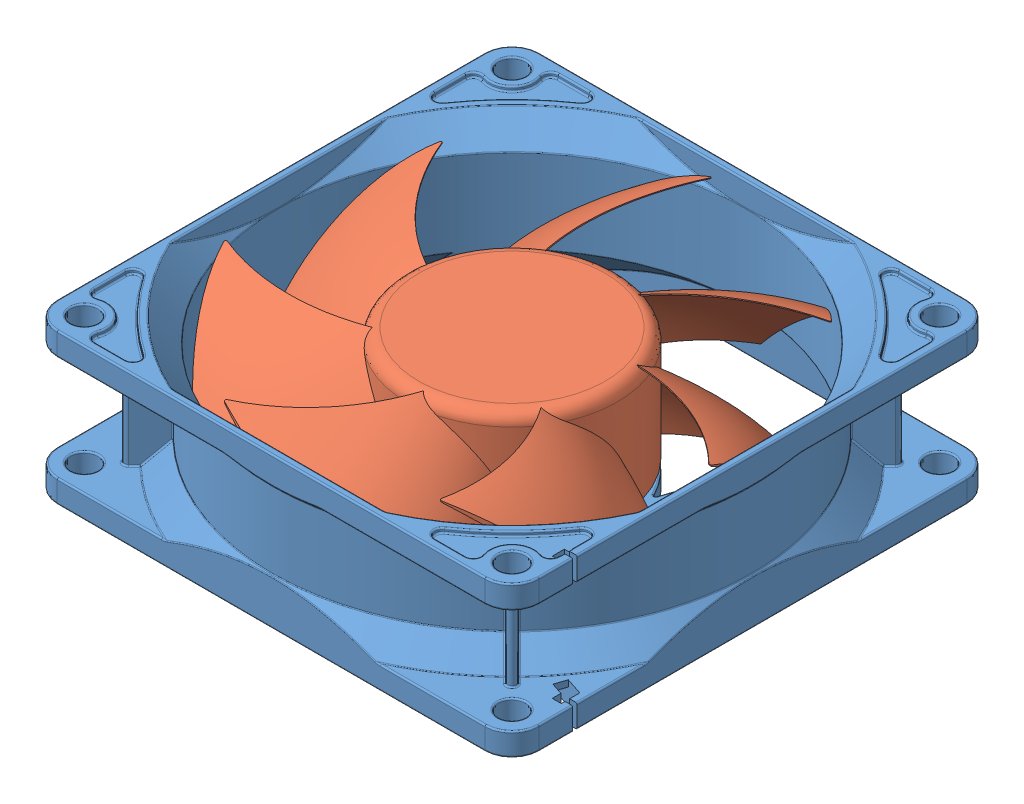
SolidWorks assembly Assem2, configuration Default. Lengths in mm.
Overall size (111.17 27.66 111.17).
3 component instances, 3 part files, 2 mates.
Components (placement in the parent):
- Part1-1: Part1 [Default] at origin size (85.02 27.66 85.07)
- Part2-1: Part2 [Default] at (0 -8 0) x (0.706618 0 -0.707595) z (0.707595 0 0.706618) size (79.24 20.79 77.99)
- Part1^Assem2-1: Part1^Assem2 [Default] at origin size (77.65 20 77.65) (hidden, virtual)
Mates (geometry in assembly coordinates):
- Coincident1: coincident anti-aligned: line of Part1-1 through (12.4429 0 -4.7464) axis (0 0 1); line of Part2-1 through (16.75 0 8.75) axis (0 0 -1)
- Distance1: distance = 1.5 mm anti-aligned: plane of Part1-1 through (0 -9.5 0) normal (0 1 0); plane of Part2-1 through (0 -8 0) normal (0 -1 0)
